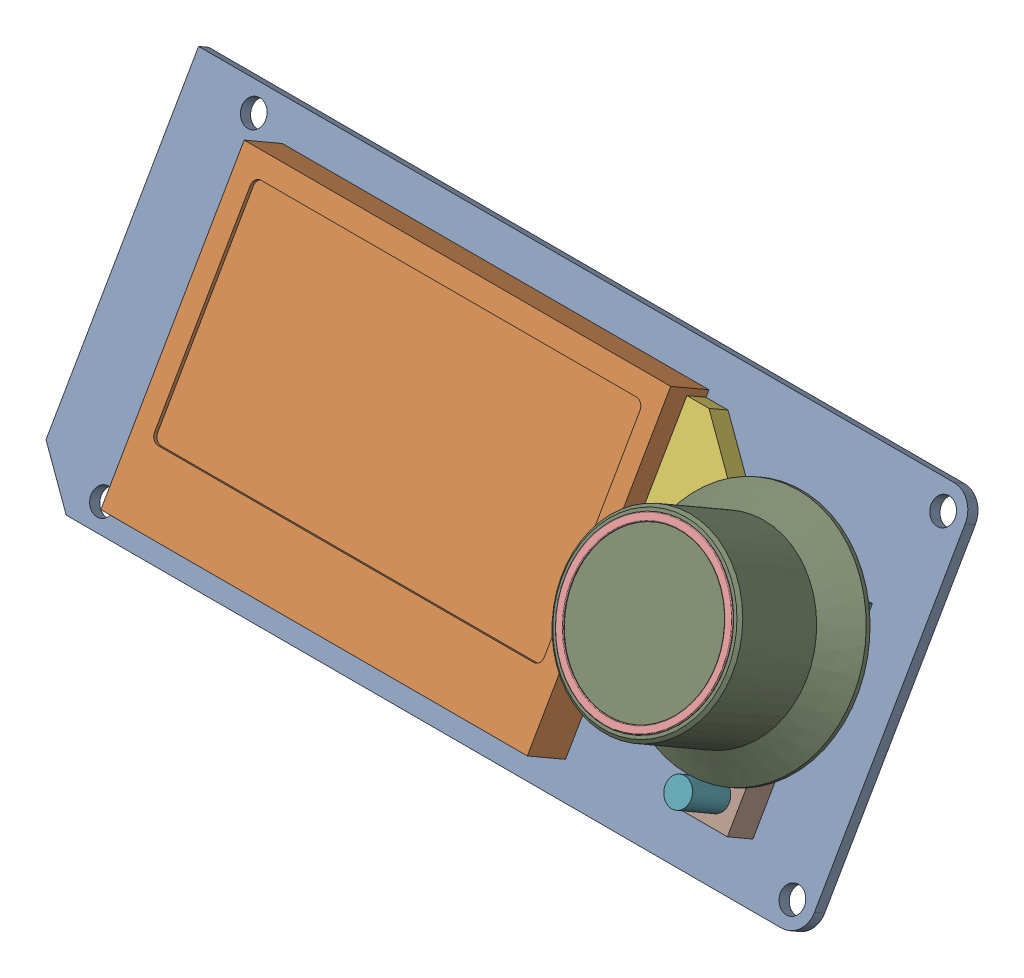
SolidWorks assembly Mini12864 Screen v1, configuration Default. Lengths in mm.
Overall size (107.75 49.06 41.97).
13 component instances, 10 part files, 0 mates.
Components (placement in the parent):
- Mini12864 Screen v1_2-1: Mini12864 Screen v1_2 [Default] at origin size (105.75 41.5 31.62)
  - Mini12864 Screen v1_4-1: Mini12864 Screen v1_4 [Default] at origin size (105.75 41.5 24.89)
  - Mini12864 Screen v1_5-1: Mini12864 Screen v1_5 [Default] at origin size (58 36.77 24.7)
  - Mini12864 Screen v1_3-1: Mini12864 Screen v1_3 [Default] at origin size (12.25 18.34 22.13)
  - Mini12864 Screen v1-1: Mini12864 Screen v1 [Default] at origin size (18.5 24.88 16.1)
  - Mini12864 Screen v1_2-1: Mini12864 Screen v1_2 [Default] at origin size (74.25 35.31 20.1)
  - Mini12864 Screen v1_6-1: Mini12864 Screen v1_6 [Default] at origin size (10 28.35 18.1)
- Kill Button-1: Kill Button [Default] at (-0.25 0 0) size (6 9.11 11.04)
  - Kill Button-1: Kill Button [Default] at origin size (3.5 6.03 6.95)
  - Kill Button_2-1: Kill Button_2 [Default] at origin size (6 7.2 6.46)
- Jog-1: Jog [Default] at (-74.0001 90.8894 -54.2015) x (1 0 0) z (0 0.866025 -0.5) size (30 16.2 30)
  - Jog-1: Jog [Default] at origin size (30 16 30)
  - Jog_2-1: Jog_2 [Default] at origin size (21.6 0.2 21.6)
